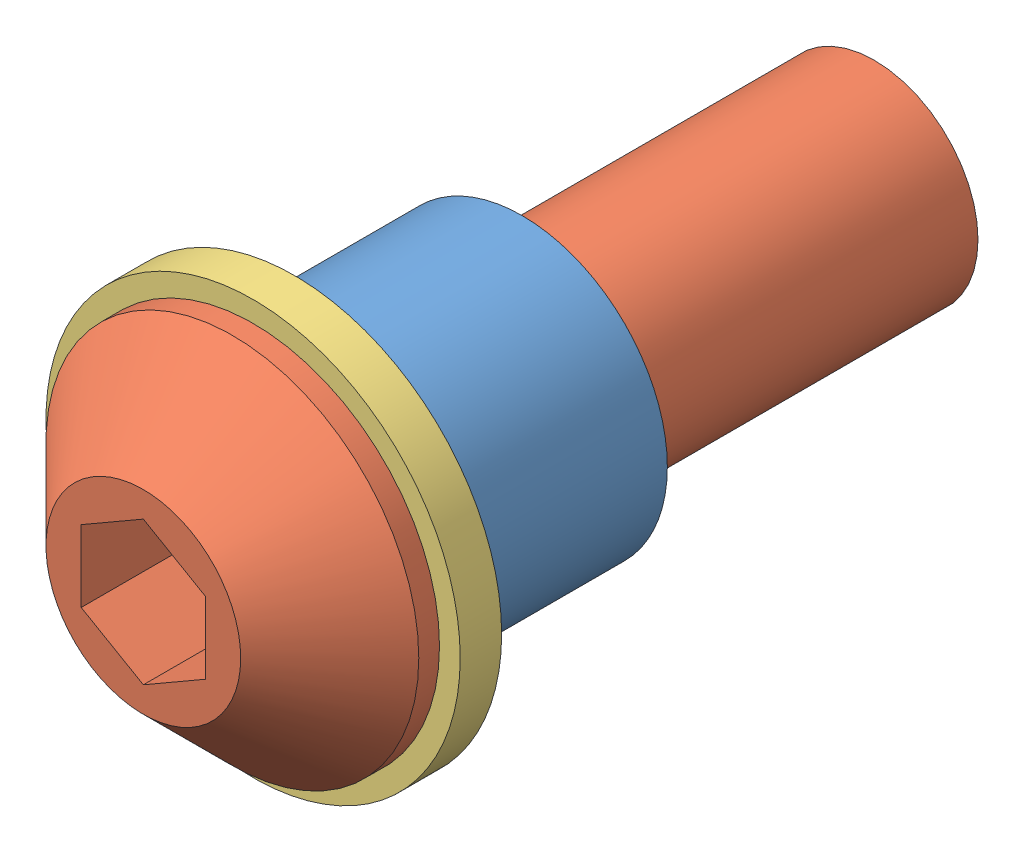
SolidWorks assembly Skrue_m_rør_kpl, configuration Default. Lengths in mm.
Overall size (20 20 35.3).
3 component instances, 3 part files, 3 mates.
Components (placement in the parent):
- 6302369-1: 6302369 [Default] at origin size (14 14 11)
- Rundhovedet BH skrue-1: Rundhovedet BH skrue [M10 x 30 - 30649] at (0 0 13) x (-1 0 0) z (0 0 1) size (18 18 35.3)
- Skiver-1: Skiver [Facetskive 10mm - 31177] at (0 0 13) x (-1 0 0) z (0 0 -1) size (20 20 2)
Mates (geometry in assembly coordinates):
- Coincident1: coincident anti-aligned: plane of 6302369-1 through (0 0 11) normal (0 0 1); plane of Skiver-1 through (0 0 11) normal (0 0 -1)
- Concentric1: concentric anti-aligned: cylinder of 6302369-1 through (0 0 11) axis (0 0 -1) radius 5; cylinder of Skiver-1 through (0 0 11) axis (0 0 1) radius 5.25
- Coincident2: coincident anti-aligned: plane of Rundhovedet BH skrue-1 through (0 0 13) normal (0 0 -1); plane of Skiver-1 through (0 0 13) normal (0 0 1)
